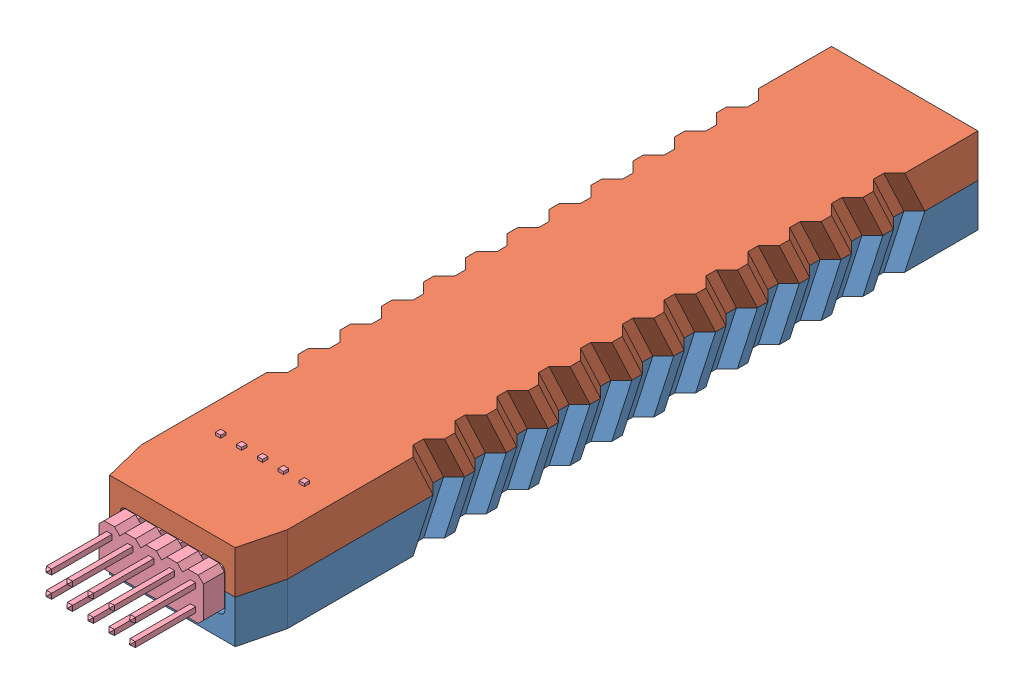
SolidWorks assembly DeviceConnectorCable, configuration Device Connector. Lengths in mm.
Overall size (14.04 8.55 78.54).
7 component instances, 6 part files, 27 mates.
Components (placement in the parent):
- DeviceEnclosureLid^DeviceConnectorCable-1: DeviceEnclosureLid^DeviceConnectorCable [Device Enclosure Lid] at (0 -4.1 -37.3) x (0 0 -1) z (1 0 0) size (70.11 6.22 14.04) (virtual)
- DeviceEnclosureBody^DeviceConnectorCable-1: DeviceEnclosureBody^DeviceConnectorCable [Device Enclosure Body] at (0 4.1 -37.3) x (0 0 -1) z (-1 0 0) size (70.5 6.52 14.04) (virtual)
- RoundCable^DeviceConnectorCable-1: RoundCable^DeviceConnectorCable [Default] at (0.001 0 -21.5457) x (0 0 -1) z (-1 0 0) size (48.31 3 8.21) (virtual)
- CONNFLY DS1030-02 TYPE4 2.00mm Pin Header Double Row Stack SMT Type-1: CONNFLY DS1030-02 TYPE4 2.00mm Pin Header Double Row Stack SMT Type [DS1021-2x5] at (4 0.1 -8.6597) x (1 0 0) z (0 0 -1) size (10 8.5 16.9)
- P75-E2-1: P75-E2 [Work] at (-3.9918 -1.7697 -26.1938) x (-1 0 0) z (0 1 0) size (1.34 14.95 1.34)
  - Barrel^P75-E2-1: Barrel^P75-E2 [Default] at origin size (1.1 13 1.1) (virtual)
  - Plunger^P75-E2-1: Plunger^P75-E2 [Default] at (0 11.05 0) x (0.999365 0 -0.035623) z (0.035623 0 0.999365) size (1.29 3.9 1.29) (virtual)
Mates (geometry in assembly coordinates):
- Coincident4: coincident aligned: plane of DeviceEnclosureLid^DeviceConnectorCable-1 through (0 -2.1 -2.3) normal (0 0 1); plane of Lid^cable-1 through (0 2.1 0.013) normal (0 0 1)
- Coincident5: coincident anti-aligned: plane of DeviceEnclosureLid^DeviceConnectorCable-1 through (0 0 -37.3) normal (0 1 0); plane of Lid^cable-1 through (0 0.1 -27.487) normal (0 -1 0)
- Concentric1: concentric anti-aligned: cylinder of Self Tapping Cross recessed Screw 4Plastic^cable-1 through (-14 -8 -8.287) axis (0 -1 0) radius 0.78; cylinder of Lid^cable-1 through (-14 2.1 -8.287) axis (0 1 0) radius 1.5
- Coincident7: coincident aligned: cone of Self Tapping Cross recessed Screw 4Plastic^cable-1 through (-14 0.48 -8.287) axis (0 -1 0); cone of Lid^cable-1 through (-14 2.1 -8.287) axis (0 -1 0)
- Concentric2: concentric anti-aligned: cylinder of Self Tapping Cross recessed Screw 4Plastic^cable-2 through (14 -8 -8.287) axis (0 -1 0) radius 0.78; cylinder of Lid^cable-1 through (14 2.1 -8.287) axis (0 1 0) radius 1.5
- Coincident8: coincident aligned: cone of Self Tapping Cross recessed Screw 4Plastic^cable-2 through (14 0.48 -8.287) axis (0 -1 0); cone of Lid^cable-1 through (14 2.1 -8.287) axis (0 -1 0)
- Coincident10: coincident aligned: plane of board^cable-1 through (-0.9944 1 -14.4999) normal (0 1 0); plane of RibbonCable^DeviceConnector-1 through (0 0 -17.6612) normal (0 1 0)
- Coincident11: coincident anti-aligned: plane of board^cable-1 through (-0.9944 1 -14.4999) normal (0 1 0); plane of PBD-20-1 through (10.4356 1 0.5001) normal (0 -1 0)
- Coincident12: coincident anti-aligned: plane of board^cable-1 through (-13.8944 1.75 0.5001) normal (0 0 1); plane of PBD-20-1 through (9.1656 -1.54 0.5001) normal (0 0 -1)
- Coincident13: coincident anti-aligned: plane of DeviceEnclosureLid^DeviceConnectorCable-1 through (0 -4.1 -37.3) normal (1 0 0); plane of PBD-20-1 through (-0.9944 -0.27 0.5001) normal (-1 0 0)
- Coincident14: coincident anti-aligned: plane of RibbonCable^DeviceConnector-1 through (0 0 -17.6612) normal (1 0 0); plane of PBD-20-1 through (-0.9944 -0.27 0.5001) normal (-1 0 0)
- Coincident15: coincident anti-aligned: plane of DeviceEnclosureLid^DeviceConnectorCable-1 through (0 -1.05 -37.3) normal (0 1 0); plane of PBD-20-1 through (10.4356 1 0.5001) normal (0 -1 0)
- Coincident16: coincident aligned: plane of board^cable-1 through (-0.9944 1 -14.4999) normal (-1 0 0); plane of PBD-20-1 through (-0.9944 -0.27 0.5001) normal (-1 0 0)
- Concentric3: concentric anti-aligned: cylinder of board^cable-1 through (13.0056 0.25 -6.9999) axis (0 1 0) radius 3.4; cylinder of EnclosureBody^cable-1 through (5.0056 3.65 -8.287) axis (0 -1 0) radius 3.1
- Coincident17: coincident aligned: plane of DeviceEnclosureLid^DeviceConnectorCable-1 through (0 -4.1 -37.3) normal (1 0 0); plane of Lid^cable-1 through (0 0.1 -27.487) normal (1 0 0)
- Coincident18: coincident anti-aligned: plane of board^cable-1 through (-13.8944 1.75 0.5001) normal (0 0 1); plane of PLD2-NN (DS-1025-05 - 2xNN) 2mm^DeviceConnector-1 through (10 1.3335 -1.6) normal (0 0 -1)
- Coincident23: coincident anti-aligned: plane of DeviceEnclosureLid^DeviceConnectorCable-1 through (-5 0 -37.3) normal (1 0 0); plane of PLD2-NN (DS-1022-04 - 2xNN) 2mm^DeviceConnectorCable-1 through (-5.27 2.9 -4.3) normal (-1 0 0)
- Coincident24: coincident anti-aligned: plane of DeviceEnclosureLid^DeviceConnectorCable-1 through (0 0 -37.3) normal (0 1 0); plane of DeviceEnclosureBody^DeviceConnectorCable-1 through (0 0 -37.3) normal (0 -1 0)
- Coincident25: coincident aligned: plane of RibbonCable^DeviceConnector-1 through (0 0 -17.6612) normal (1 0 0); plane of PLD2-NN (DS-1022-04 - 2xNN) 2mm^DeviceConnectorCable-1 through (0 0 0) normal (1 0 0)
- Coincident26: coincident anti-aligned: plane of PLD2-NN (DS-1022-04 - 2xNN) 2mm^DeviceConnectorCable-1 through (4 0 -4.3) normal (0 0 -1); plane of DeviceEnclosureBody^DeviceConnectorCable-1 through (3.5 0.1 -4.3) normal (0 0 1)
- Coincident28: coincident aligned: plane of RibbonCable^DeviceConnector-1 through (0 0 -17.6612) normal (0 1 0); plane of PLD2-NN (DS-1022-04 - 2xNN) 2mm^DeviceConnectorCable-1 through (4 0 0) normal (0 1 0)
- Coincident29: coincident aligned: plane of DeviceEnclosureLid^DeviceConnectorCable-1 through (0 -2.1 -2.3) normal (0 0 1); plane of DeviceEnclosureBody^DeviceConnectorCable-1 through (0 2.1 -2.3) normal (0 0 1)
- Coincident30: coincident anti-aligned: plane of PLD2-NN (DS-1022-04 - 2xNN) 2mm^DeviceConnectorCable-1 through (4 0 0) normal (0 1 0); plane of DeviceEnclosureBody^DeviceConnectorCable-1 through (0 0 -37.3) normal (0 -1 0)
- Coincident31: coincident anti-aligned: plane of PLD2-NN (DS-1022-04 - 2xNN) 2mm^DeviceConnectorCable-1 through (0 0 0) normal (1 0 0); plane of DeviceEnclosureBody^DeviceConnectorCable-1 through (0 4.1 -37.3) normal (-1 0 0)
- Coincident32: coincident anti-aligned: plane of DeviceEnclosureBody^DeviceConnectorCable-1 through (0 2.1 -37.3) normal (0 -1 0); plane of CONNFLY DS1030-03 2.00mm Pin Header Double Row Stack SMT Type-1 through (-3 2.1 -2.2597) normal (0 1 0)
- Width1: width anti-aligned: plane of DeviceEnclosureBody^DeviceConnectorCable-1 through (-5 0 -37.3) normal (1 0 0); plane of CONNFLY DS1030-03 2.00mm Pin Header Double Row Stack SMT Type-1 through (5 0 -37.3) normal (-1 0 0); plane of DeviceEnclosureBody^DeviceConnectorCable-1 through (-5 -1.9 -2.2597) normal (-1 0 0); plane of CONNFLY DS1030-03 2.00mm Pin Header Double Row Stack SMT Type-1 through (5 -1.9 -2.2597) normal (1 0 0)
- Coincident33: coincident aligned: plane of DeviceEnclosureLid^DeviceConnectorCable-1 through (7 -2.1 -37.3) normal (1 0 0); plane of DeviceEnclosureBody^DeviceConnectorCable-1 through (7 2.1 -37.3) normal (1 0 0)
